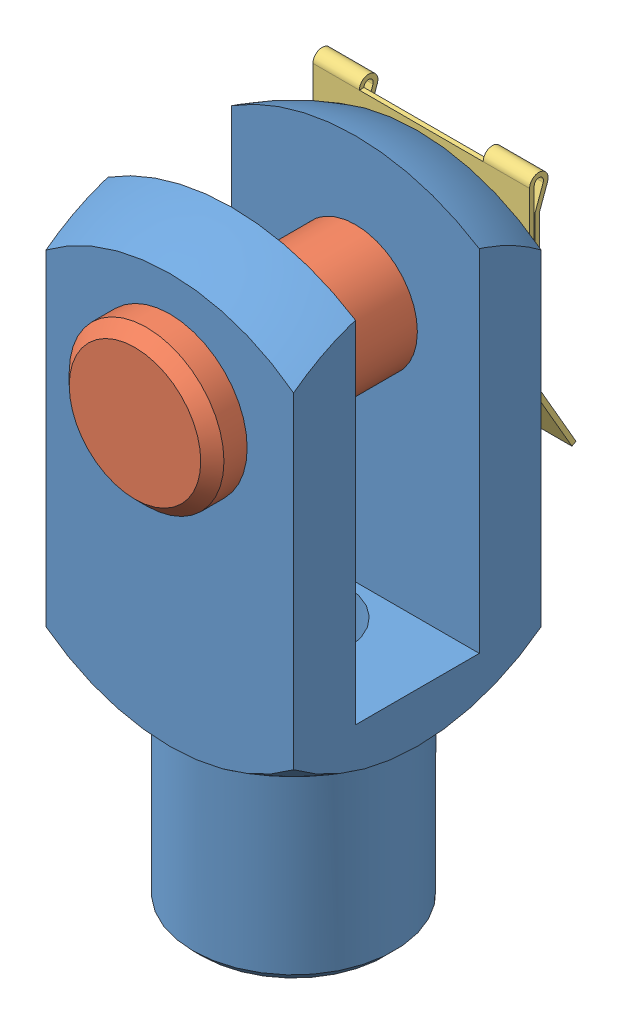
SolidWorks assembly Fork joint GN 751-16-32-M16-SL, configuration Default. Lengths in mm.
Overall size (32 81.95 43.05).
4 component instances, 3 part files, 0 mates.
Components (placement in the parent):
- Fork joint GN 751-16-32-M16-SL.stp-1: Fork joint GN 751-16-32-M16-SL.stp [Default] at origin size (32 81.95 43.05)
  - _Fork joint GN 751-16-32-M16-SL-1.stp-1: _Fork joint GN 751-16-32-M16-SL-1.stp [Default] at origin size (32 81.95 32)
  - _Fork joint GN 751-16-32-M16-SL-2.stp-1: _Fork joint GN 751-16-32-M16-SL-2.stp [Default] at (0 64 16) x (0 0 -1) z (-1 0 0) size (43.05 20 20)
  - _Fork joint GN 751-16-32-M16-SL-3.stp-1: _Fork joint GN 751-16-32-M16-SL-3.stp [Default] at (0 64 -17.7) x (0 0 -1) z (1 0 0) size (6 34 28)
